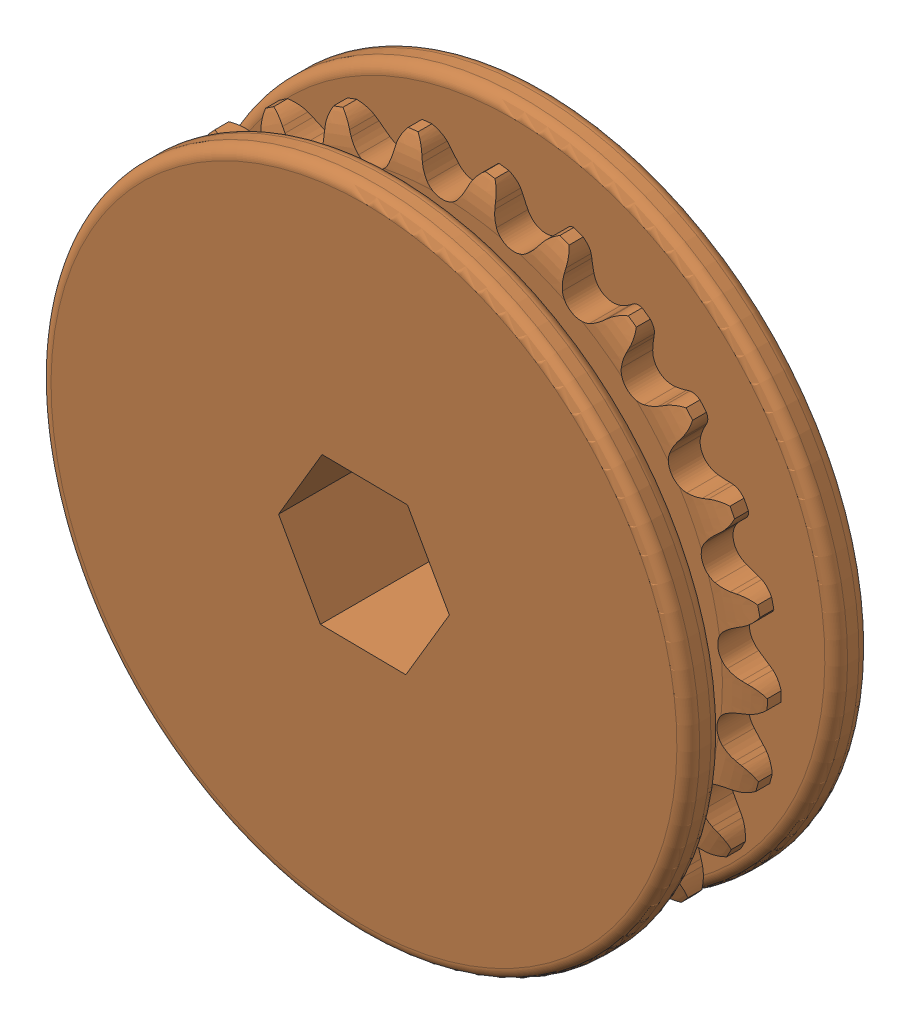
SolidWorks assembly moytortt, configuration Predeterminado. Lengths in mm.
Overall size (57.63 57.63 18).
2 component instances, 2 part files, 3 mates.
Components (placement in the parent):
- Pieza2-1: Pieza2 [Predeterminado] at (-3.6984 2.9504 0) size (30 30 2)
- Sprocket_26-1: Sprocket_26 [Predeterminado] at (-3.6984 2.9504 10) x (0.999938 -0.011163 0) z (0 0 1) size (57 57 16)
Mates (geometry in assembly coordinates):
- Coincidente1: coincident: plane of Pieza2-1 through (-11.2035 3.0342 2) normal (0.871553 0.490302 0); plane of Sprocket_26-1 through (-7.5235 -3.5073 17.1853) normal (0.871553 0.490302 0)
- Coincidente2: coincident: plane of Pieza2-1 through (-7.3784 9.4919 2) normal (0.86039 -0.509636 0); plane of Sprocket_26-1 through (-11.2035 3.0342 17.1853) normal (0.86039 -0.509636 0)
- Coincidente3: coincident anti-aligned: plane of Pieza2-1 through (-3.6984 2.9504 2) normal (0 0 1); plane of Sprocket_26-1 through (-3.6984 2.9504 2) normal (0 0 -1)
